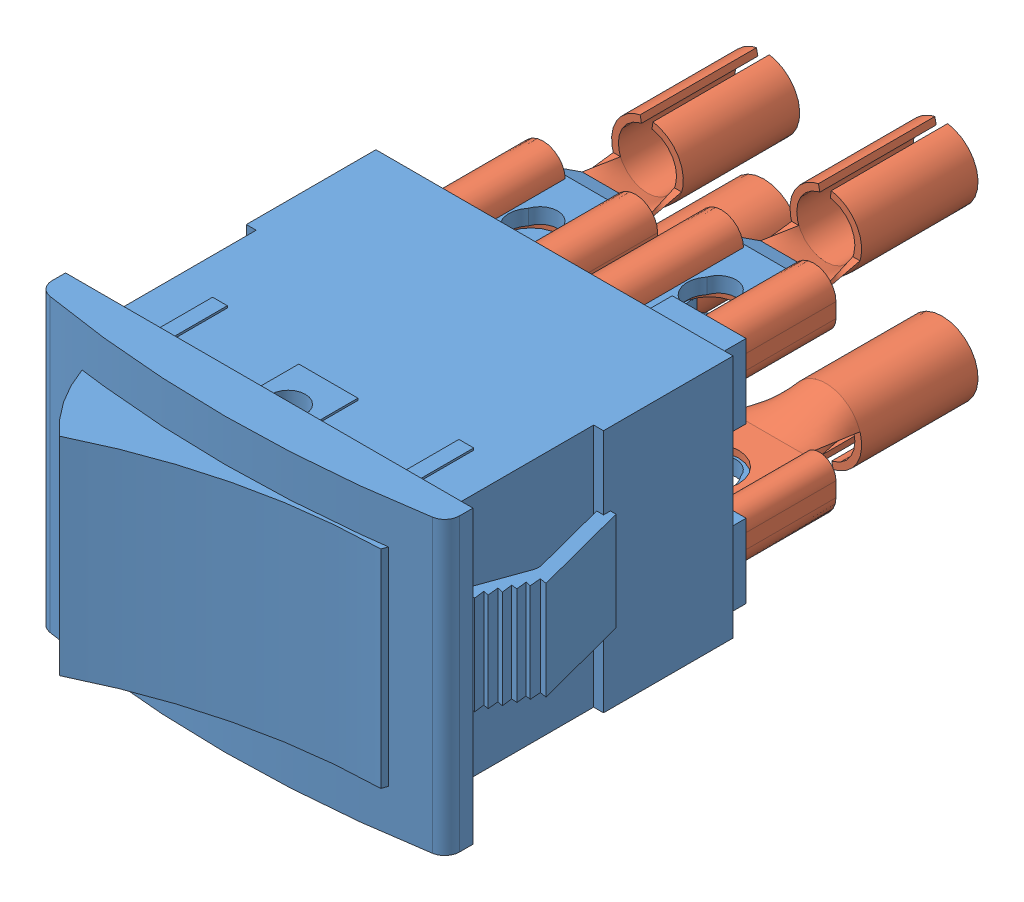
SolidWorks assembly Rocker Switch, configuration Default. Lengths in mm.
Overall size (21.56 15.01 35.99).
5 component instances, 2 part files, 12 mates.
Components (placement in the parent):
- Rocker Switch-1: Rocker Switch [Default] at origin size (21.56 15.01 28.09)
- Terminal-F-5: Terminal-F [Default] at (-5.207 -2.8555 -21.7071) x (0 1 0) z (0 0 1) size (3.88 7.05 19)
- Terminal-F-6: Terminal-F [Default] at (3.9878 -4.3795 -21.7071) x (0 1 0) z (0 0 1) size (3.88 7.05 19)
- Terminal-F-7: Terminal-F [Default] at (-5.207 2.8555 -21.7071) x (0 -1 0) z (0 0 1) size (3.88 7.05 19)
- Terminal-F-9: Terminal-F [Default] at (3.9878 4.3795 -21.7071) x (0 -1 0) z (0 0 1) size (3.88 7.05 19)
Mates (geometry in assembly coordinates):
- Concentric61: concentric aligned: cylinder of Rocker Switch-1 through (-5.207 -2.0955 -18.7071) axis (0 -1 0) radius 1.143; cylinder of Terminal-F-5 through (-5.207 -0.8055 -18.7071) axis (0 -1 0) radius 1.5
- Coincident61: coincident anti-aligned: plane of Rocker Switch-1 through (-4.572 -2.0955 -21.8632) normal (0 1 0); plane of Terminal-F-5 through (-7.382 -2.0955 -11.7071) normal (0 -1 0)
- Parallel61: parallel anti-aligned: plane of Rocker Switch-1 through (-2.8321 -2.0955 -7.7216) normal (1 0 0); plane of Terminal-F-5 through (-2.032 -2.8555 -11.7071) normal (-1 0 0)
- Concentric71: concentric aligned: cylinder of Rocker Switch-1 through (3.9878 -3.6195 -18.7071) axis (0 -1 0) radius 1.143; cylinder of Terminal-F-6 through (3.9878 -2.3295 -18.7071) axis (0 -1 0) radius 1.5
- Coincident71: coincident anti-aligned: plane of Rocker Switch-1 through (4.572 -3.6195 -21.8632) normal (0 1 0); plane of Terminal-F-6 through (1.8128 -3.6195 -11.7071) normal (0 -1 0)
- Parallel71: parallel anti-aligned: plane of Rocker Switch-1 through (6.3627 -3.6195 -7.7216) normal (1 0 0); plane of Terminal-F-6 through (7.1628 -4.3795 -11.7071) normal (-1 0 0)
- Concentric81: concentric anti-aligned: cylinder of Rocker Switch-1 through (-5.207 2.8829 -18.7071) axis (0 -1 0) radius 1.143; cylinder of Terminal-F-7 through (-5.207 0.8055 -18.7071) axis (0 1 0) radius 1.5
- Coincident81: coincident anti-aligned: plane of Rocker Switch-1 through (-4.572 2.0955 -16.2052) normal (0 -1 0); plane of Terminal-F-7 through (-3.032 2.0955 -11.7071) normal (0 1 0)
- Parallel81: parallel anti-aligned: plane of Rocker Switch-1 through (-7.5819 2.8829 -21.6916) normal (-1 0 0); plane of Terminal-F-7 through (-8.382 2.8555 -11.7071) normal (1 0 0)
- Concentric91: concentric: cylinder of Rocker Switch-1 through (3.9878 4.4069 -18.7071) axis (0 -1 0) radius 1.143; cylinder of Terminal-F-9 through (5.5593 2.4969 -7.3983) axis (-1 0 0) radius 1.5
- Coincident91: coincident: plane of Rocker Switch-1 through (4.572 3.6195 -14.7066) normal (0 -1 0); plane of Terminal-F-9 through (4.2693 4.6719 -0.3983) normal (-1 0 0)
- Parallel91: parallel: plane of Rocker Switch-1 through (1.6129 0 0) normal (-1 0 0); plane of Terminal-F-9 through (3.5093 -0.6781 -0.3983) normal (0 1 0)
